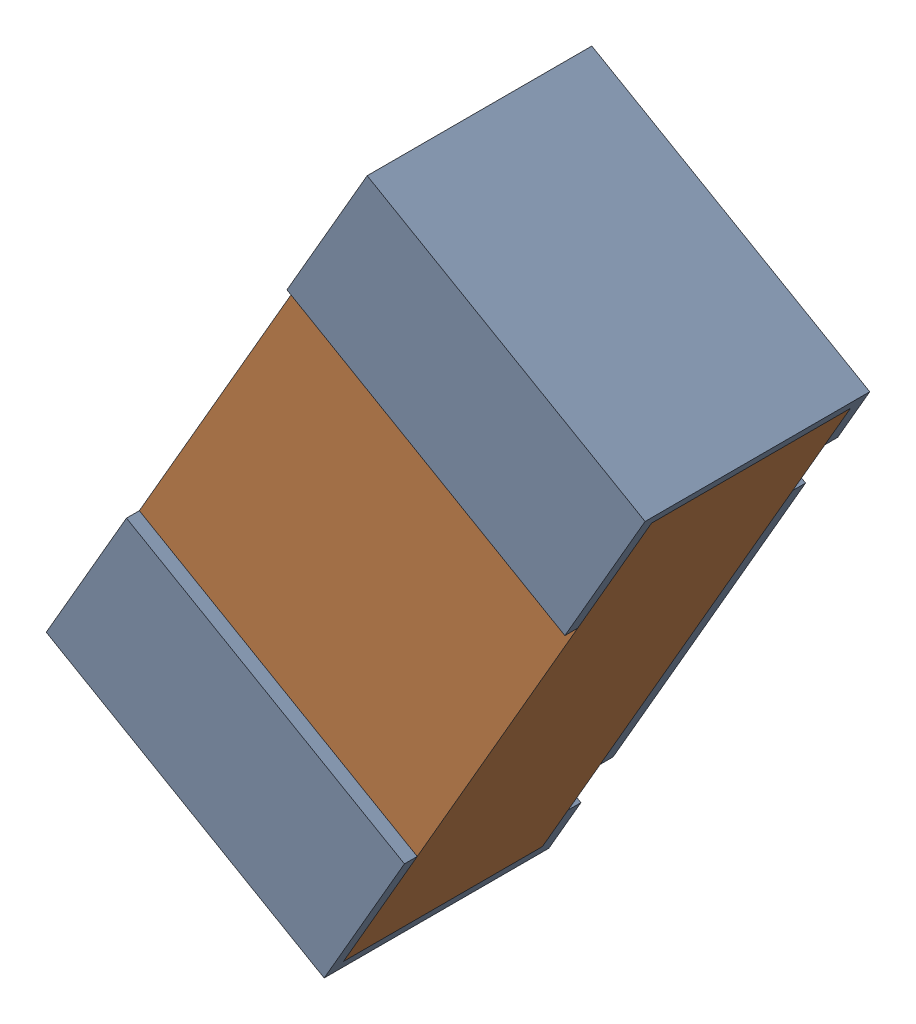
SolidWorks assembly R10, configuration Default. Lengths in mm.
Overall size (0.93 1.12 0.35).
3 component instances, 2 part files, 0 mates.
Components (placement in the parent):
- R10-subassembly-1-1: R10-subassembly-1 [Default] at (-4.2164 4.125 -1.6307) x (-0.5 -0.866025 0) z (0.866025 -0.5 0) size (1 0.35 0.5)
  - 0402 resistor-1: 0402 resistor [Default] at origin size (1 0.35 0.5)
  - 0402 resistor-1-1: 0402 resistor-1 [Default] at origin size (0.96 0.31 0.5)
